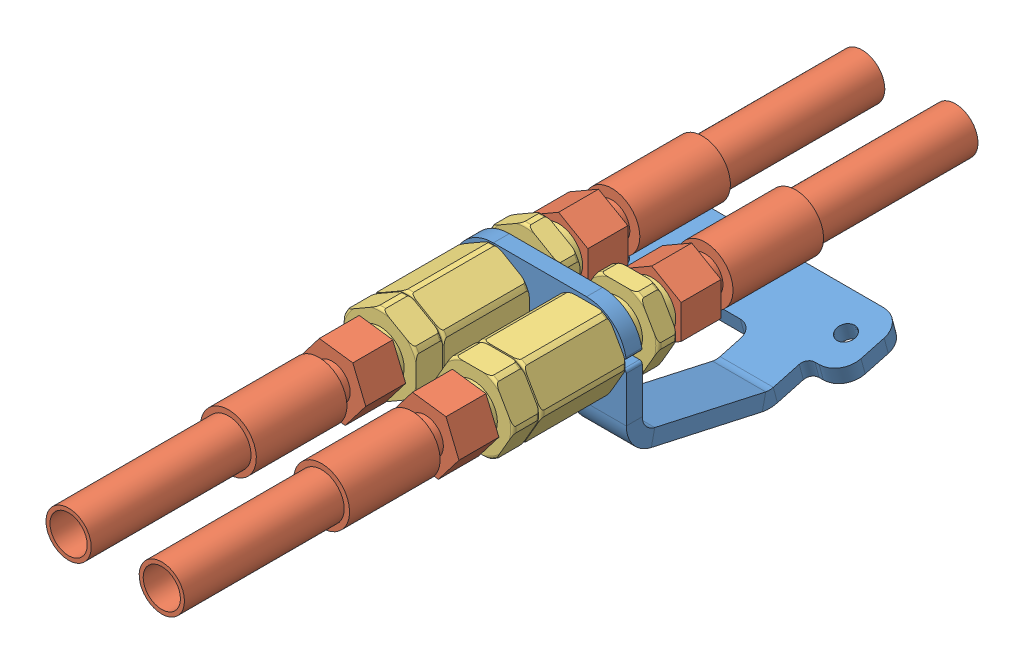
SolidWorks assembly Holder_m_rotorled_vip1_kpl, configuration Default. Lengths in mm.
Overall size (90 60.82 298).
11 component instances, 7 part files, 27 mates.
Components (placement in the parent):
- 6340251-3: 6340251 [Default] at origin size (90 55.83 93.56)
- Slange ende lige-1: Slange ende lige [3-8] at (-17.5 115 -24.5) x (1 0 0) z (0 0 -1) size (22 25.4 114)
- Slange ende lige-2: Slange ende lige [3-8] at (17.5 115 -24.5) x (1 0 0) z (0 0 -1) size (22 25.4 114)
- Sætskruer-1: Sætskruer [M8 x 25 Rustfri - 30134] at (35 130.971 -108.3343) x (-0.991408 0.033856 -0.126352) z (0 -0.965926 -0.258819) (suppressed, hidden)
- HBS_rotorled_3_8_kpl-1: HBS_rotorled_3_8_kpl [Default] at (17.5 115 -32.5) x (0.866025 0.5 0) z (0 0 1) size (27 30.58 87)
- HBS_rotorled_3_8_kpl-2: HBS_rotorled_3_8_kpl [Default] at (-17.5 115 -32.5) size (27 30.58 87)
- HBS_rotorled_1_2_kpl-1: HBS_rotorled_1_2_kpl [Default] at (-20 142.5 -35) x (0.866025 -0.5 0) z (0 0 1) (suppressed, hidden)
- 6340251_gl-2: 6340251_gl [Default] at (-1.4081 -32.649 0) x (0.999971 0.007659 0) z (0 0 1) (suppressed, hidden)
- Slange ende lige-3: Slange ende lige [3-8] at (17.5 115 45.5) x (-0.923728 -0.383049 0) z (0 0 1) size (22 25.4 114)
- Slange ende lige-4: Slange ende lige [3-8] at (-17.5 115 45.5) x (-0.923728 -0.383049 0) z (0 0 1) size (22 25.4 114)
- 6340251_A-1: 6340251_A [Default] at (0 -25 0) (suppressed, hidden)
Mates (geometry in assembly coordinates):
- Concentric4: concentric anti-aligned: cylinder of 6340251-3 through (35 87 -79.9198) axis (0 -0.965926 -0.258819) radius 3.4; cylinder of assembly through (35 101.7035 -116.1765) axis (0 0.965926 0.258819) radius 4
- Coincident3: coincident anti-aligned: plane of 6340251-3 through (17.5 60.4711 19.0876) normal (0 0.965926 0.258819)
- Concentric5: concentric anti-aligned: cylinder of 6340251-3 through (17.5 115 -6) axis (0 0 1) radius 9.15; cylinder of HBS_rotorled_3_8_kpl-1 through (17.5 115 -32.5) axis (0 0 -1) radius 9
- Coincident4: coincident anti-aligned: plane of 6340251-3 through (17.5 115 0) normal (0 0 1); plane of HBS_rotorled_3_8_kpl-1 through (10.5 127.1244 0) normal (0 0 -1)
- Parallel3: parallel aligned: plane of 6340251-3 through (17.5 130 -6) normal (0 1 0); plane of HBS_rotorled_3_8_kpl-1 through (25.2942 128.5 54.5) normal (0 1 0)
- Concentric6: concentric anti-aligned: cylinder of 6340251-3 through (-17.5 115 -6) axis (0 0 1) radius 9.15; cylinder of assembly through (-20 142.5 -35) axis (0 0 -1) radius 12
- Coincident6: coincident anti-aligned: plane of 6340251-3 through (17.5 115 0) normal (0 0 1); plane of assembly through (-11.7 156.876 0) normal (0 0 -1)
- Parallel4: parallel aligned: plane of 6340251-3 through (17.5 130 -6) normal (0 1 0); plane of assembly through (-10.7624 158.5 55) normal (0 1 0)
- Concentric7: concentric anti-aligned: cylinder of Slange ende lige-1 through (-17.5 115 -138.5) axis (0 0 1) radius 3.5; cylinder of HBS_rotorled_3_8_kpl-2 through (-17.5 115 -32.5) axis (0 0 -1) radius 9
- Concentric9: concentric anti-aligned: cylinder of HBS_rotorled_3_8_kpl-1 through (17.5 115 -32.5) axis (0 0 -1) radius 9; cylinder of assembly through (17.5 110 -6) axis (0 0 1) radius 9.15
- Coincident8: coincident anti-aligned: plane of HBS_rotorled_3_8_kpl-1 through (10.5 127.1244 0) normal (0 0 -1); plane of assembly through (17.5 110 0) normal (0 0 1)
- Concentric10: concentric: cylinder of HBS_rotorled_1_2_kpl-1 through (-20 142.5 -35) axis (0 0 -1) radius 12; cylinder of 6340251_gl-2 through (-20 142.5 -6) axis (0 0 1) radius 12.15
- Concentric11: concentric anti-aligned: cylinder of Slange ende lige-2 through (17.5 115 -44.5) axis (0 0 1) radius 6.75; cylinder of HBS_rotorled_3_8_kpl-1 through (17.5 115 -32.5) axis (0 0 -1) radius 9
- Distance2: distance = 8 mm anti-aligned: plane of Slange ende lige-2 through (17.5 102.2983 -24.5) normal (0 0 1); plane of HBS_rotorled_3_8_kpl-1 through (33.0885 115 -32.5) normal (0 0 -1)
- Concentric12: concentric anti-aligned: cylinder of 6340251-3 through (-17.5 115 -6) axis (0 0 1) radius 9.15; cylinder of HBS_rotorled_3_8_kpl-2 through (-17.5 115 -32.5) axis (0 0 -1) radius 9
- Coincident9: coincident anti-aligned: plane of 6340251-3 through (17.5 115 0) normal (0 0 1); plane of HBS_rotorled_3_8_kpl-2 through (-17.5 129 0) normal (0 0 -1)
- Coincident10: coincident aligned: plane of Slange ende lige-1 through (-17.5 102.2983 -39.5) normal (0 0 -1); plane of Slange ende lige-2 through (17.5 102.2983 -39.5) normal (0 0 -1)
- Parallel5: parallel anti-aligned: plane of Slange ende lige-1 through (-17.5 115 -24.5) normal (0 -1 0); plane of assembly through (0 0 0) normal (0 1 0)
- Parallel6: parallel aligned: plane of HBS_rotorled_3_8_kpl-2 through (-17.5 115 -32.5) normal (0 1 0); plane of assembly through (0 0 0) normal (0 1 0)
- Parallel7: parallel anti-aligned: plane of Slange ende lige-2 through (17.5 115 -24.5) normal (0 -1 0); plane of assembly through (0 0 0) normal (0 1 0)
- Concentric13: concentric aligned: cylinder of HBS_rotorled_3_8_kpl-1 through (17.5 115 -32.5) axis (0 0 -1) radius 9; cylinder of Slange ende lige-3 through (17.5 115 65.5) axis (0 0 -1) radius 6.75
- Concentric14: concentric aligned: cylinder of HBS_rotorled_3_8_kpl-2 through (-17.5 115 -32.5) axis (0 0 -1) radius 9; cylinder of Slange ende lige-4 through (-17.5 115 65.5) axis (0 0 -1) radius 6.75
- Distance3: distance = 3 mm anti-aligned: plane of HBS_rotorled_3_8_kpl-2 through (-17.5 129 42.5) normal (0 0 1); plane of Slange ende lige-4 through (-12.6346 103.2671 45.5) normal (0 0 -1)
- Distance4: distance = 3 mm anti-aligned: plane of HBS_rotorled_3_8_kpl-1 through (10.5 127.1244 42.5) normal (0 0 1); plane of Slange ende lige-3 through (22.3654 103.2671 45.5) normal (0 0 -1)
- Coincident11: coincident: plane of 6340251_A-1; plane of assembly through (0 0 0) normal (1 0 0)
- Coincident12: coincident aligned: plane of 6340251-3 through (17.5 115 -6) normal (0 0 -1); plane of assembly through (20 110 -6) normal (0 0 -1)
- Coincident13: coincident aligned: plane of 6340251-3 through (17.5 130 -6) normal (0 1 0); plane of assembly through (20 125 -6) normal (0 1 0)
